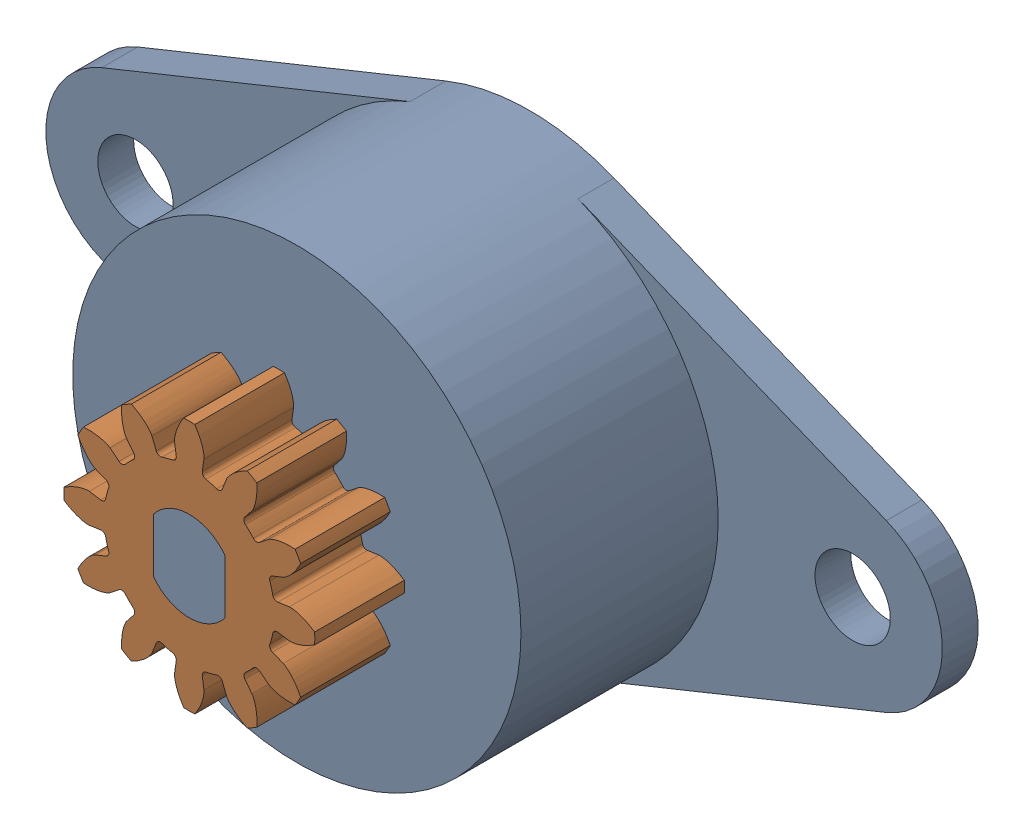
SolidWorks assembly FRT-D2-152-G1_1, configuration Default. Lengths in mm.
Overall size (50 25 19).
2 component instances, 2 part files, 0 mates.
Components (placement in the parent):
- FRT-D2-152-1: FRT-D2-152 [Default] at origin size (50 25 19)
- FRT-D2-G1 12mm Gear-2: FRT-D2-G1 12mm Gear [Default] at (0 0 14) x (0 -1 0) z (0 0 1) size (14 14 5)
